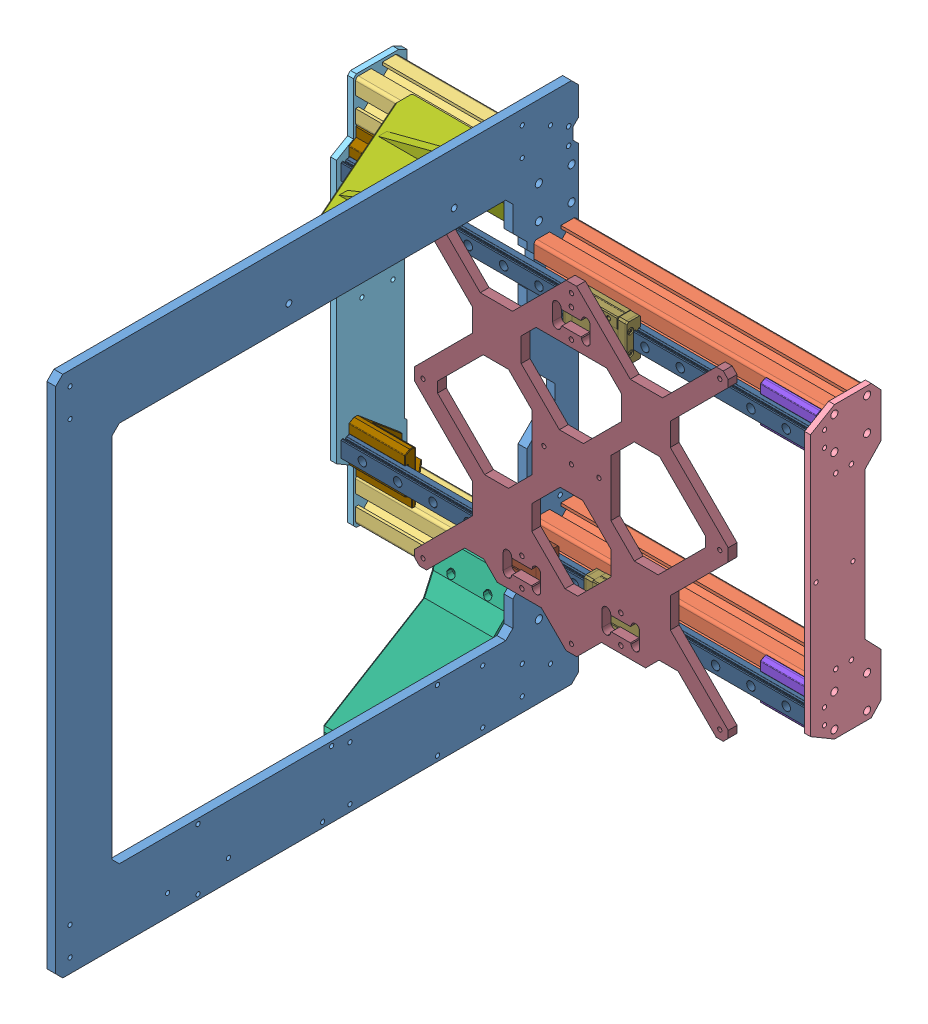
SolidWorks assembly Prusa Frame, configuration Default. Lengths in mm.
Overall size (339.55 370 375).
19 component instances, 13 part files, 54 mates.
Components (placement in the parent):
- Z Frame-2: Z Frame [Default] x (0 1 0) z (1 0 0) size (370 370 6.25)
- 3030 205mm-1: 3030 205mm [Default] at (0 -85 -156.75) x (0 0 -1) z (1 0 0) size (30 30 205)
- 3030 205mm-2: 3030 205mm [Default] at (0 85 -156.75) x (0 0 -1) z (1 0 0) size (30 30 205)
- 3030 120mm-1: 3030 120mm [Default] at (-126.25 -122 -156.75) x (0 1 0) z (1 0 0) size (30 30 120)
- 3030 120mm-2: 3030 120mm [Default] at (-126.25 122 -156.75) x (0 1 0) z (1 0 0) size (30 30 120)
- Front Plate-1: Front Plate [Default] at (0 0 -128.25) x (0 1 0) z (0 0 1) size (205 4.15 50)
- Rear Plate-1: Rear Plate [Default] at (-130.4 0 -175.25) x (0 1 0) z (1 0 0) size (278 50 4.15)
- Einsey Frame Brace-1: Einsey Frame Brace [Default] at (-6.25 -185 -173.25) x (-1 0 0) z (0 0 1) size (56.01 42 143.3)
- PSU Frame Brace-1: PSU Frame Brace [Default] at (-6.25 -185 -173.25) x (-1 0 0) z (0 0 1) size (86.01 54.03 191)
- MGN12 Front-1: MGN12 Front [Default] at (165 -85 -141.75) x (0 -1 0) z (-1 0 0) size (28.98 6 40)
- MGN12 Rear-1: MGN12 Rear [Left] at (-126.25 -107 -141.75) x (0 1 0) z (1 0 0) size (37.75 35 40)
- MGN12 Rear-3: MGN12 Rear [Left] at (-86.25 107 -141.75) x (0 -1 0) z (-1 0 0) size (37.75 35 40)
- MGN12 Front-3: MGN12 Front [Default] at (165 85 -141.75) x (0 -1 0) z (-1 0 0) size (28.98 6 40)
- MGN12 330mm Rail-1: MGN12 330mm Rail [Default] at (-110.5 -85 -138.75) size (330 12 8.07)
- MGN12 330mm Rail-2: MGN12 330mm Rail [Default] at (189.5 85 -138.75) x (-1 0 0) z (0 0 1) size (330 12 8.07)
- MGN12C-1: MGN12C [Default] at (-11.1526 -85 -135.75) size (34.7 27 10)
- MGN12H-1: MGN12H [Default] at (50.9974 -85 -135.75) size (45.4 27 10)
- MGN12H-2: MGN12H [Default] at (35.9974 85 -135.75) size (45.4 27 10)
- Bed Frame-1: Bed Frame [Default] at (48.6974 -1.5 -125.75) x (0 1 0) z (0 0 1) size (227 222 6.25)
Mates (geometry in assembly coordinates):
- Coincident4: coincident: point of Z Frame-2
- Parallel1: parallel aligned: plane of Z Frame-2 through (0 0 0) normal (1 0 0)
- Parallel2: parallel aligned: plane of Z Frame-2 through (0 0 0) normal (0 1 0)
- Coincident6: coincident anti-aligned: plane of Z Frame-2 through (0 0 0) normal (1 0 0); plane of 3030 205mm-1 through (0 -72 -169.75) normal (-1 0 0)
- Concentric4: concentric anti-aligned: cylinder of Z Frame-2 through (-6.25 73.4 -145.15) axis (1 0 0) radius 2.55; cylinder of 3030 205mm-2 through (205 73.4 -145.15) axis (-1 0 0) radius 2.55
- Coincident7: coincident anti-aligned: plane of Z Frame-2 through (0 0 0) normal (1 0 0); plane of 3030 205mm-2 through (0 98 -169.75) normal (-1 0 0)
- Concentric5: concentric anti-aligned: cylinder of Z Frame-2 through (-6.25 96.6 -168.35) axis (1 0 0) radius 2.55; cylinder of 3030 205mm-2 through (205 96.6 -168.35) axis (-1 0 0) radius 2.55
- Concentric6: concentric anti-aligned: cylinder of Z Frame-2 through (-6.25 -96.6 -145.15) axis (1 0 0) radius 2.55; cylinder of 3030 205mm-1 through (205 -96.6 -145.15) axis (-1 0 0) radius 2.55
- Concentric7: concentric anti-aligned: cylinder of Z Frame-2 through (-6.25 -73.4 -168.35) axis (1 0 0) radius 2.55; cylinder of 3030 205mm-1 through (205 -73.4 -168.35) axis (-1 0 0) radius 2.55
- Concentric8: concentric anti-aligned: cylinder of Z Frame-2 through (-6.25 -133.6 -145.15) axis (1 0 0) radius 2.55; cylinder of 3030 120mm-1 through (-6.25 -133.6 -145.15) axis (-1 0 0) radius 2.55
- Coincident8: coincident anti-aligned: plane of Z Frame-2 through (-6.25 0 0) normal (-1 0 0); plane of 3030 120mm-1 through (-6.25 -135 -169.75) normal (1 0 0)
- Concentric9: concentric anti-aligned: cylinder of Z Frame-2 through (-6.25 -110.4 -168.35) axis (1 0 0) radius 2.55; cylinder of 3030 120mm-1 through (-6.25 -110.4 -168.35) axis (-1 0 0) radius 2.55
- Concentric10: concentric anti-aligned: cylinder of Z Frame-2 through (-6.25 133.6 -145.15) axis (1 0 0) radius 2.55; cylinder of 3030 120mm-2 through (-6.25 133.6 -145.15) axis (-1 0 0) radius 2.55
- Concentric11: concentric anti-aligned: cylinder of Z Frame-2 through (-6.25 110.4 -168.35) axis (1 0 0) radius 2.55; cylinder of 3030 120mm-2 through (-6.25 110.4 -168.35) axis (-1 0 0) radius 2.55
- Coincident9: coincident anti-aligned: plane of Z Frame-2 through (-6.25 0 0) normal (-1 0 0); plane of 3030 120mm-2 through (-6.25 109 -169.75) normal (1 0 0)
- Concentric12: concentric aligned: cylinder of 3030 205mm-2 through (205 96.6 -145.15) axis (-1 0 0) radius 2.55; cylinder of Front Plate-1 through (209.15 96.6 -145.15) axis (-1 0 0) radius 2.5
- Coincident10: coincident anti-aligned: plane of 3030 205mm-2 through (205 98 -169.75) normal (1 0 0); plane of Front Plate-1 through (205 0 -128.25) normal (-1 0 0)
- Concentric13: concentric aligned: cylinder of 3030 205mm-1 through (205 -96.6 -168.35) axis (-1 0 0) radius 2.55; cylinder of Front Plate-1 through (209.15 -96.6 -168.35) axis (-1 0 0) radius 2.5
- Concentric14: concentric aligned: cylinder of 3030 120mm-1 through (-6.25 -133.6 -145.15) axis (-1 0 0) radius 2.55; cylinder of Rear Plate-1 through (-126.25 -133.6 -145.15) axis (-1 0 0) radius 2.5
- Coincident11: coincident anti-aligned: plane of 3030 120mm-2 through (-126.25 109 -169.75) normal (-1 0 0); plane of Rear Plate-1 through (-126.25 0 -175.25) normal (1 0 0)
- Concentric15: concentric aligned: cylinder of 3030 120mm-2 through (-6.25 133.6 -168.35) axis (-1 0 0) radius 2.55; cylinder of Rear Plate-1 through (-126.25 133.6 -168.35) axis (-1 0 0) radius 2.5
- Tangent2: tangent anti-aligned: plane of Z Frame-2 through (-6.25 0 0) normal (-1 0 0); face of ?
- Tangent3: tangent anti-aligned: plane of 3030 120mm-1 through (-6.25 -126 -141.75) normal (0 0 1); edge_curve of ?
- Tangent4: tangent anti-aligned: plane of 3030 120mm-1 through (-6.25 -137 -143.75) normal (0 -1 0); edge_curve of ?
- Tangent5: tangent anti-aligned: plane of Z Frame-2 through (-6.25 0 0) normal (-1 0 0); edge_curve of ?
- Tangent6: tangent anti-aligned: plane of 3030 120mm-2 through (-6.25 135 -141.75) normal (0 0 1); edge_curve of ?
- Tangent7: tangent anti-aligned: plane of 3030 120mm-2 through (-6.25 137 -152.75) normal (0 1 0); edge_curve of ?
- Coincident12: coincident anti-aligned: plane of 3030 205mm-1 through (205 -72 -141.75) normal (0 0 1); plane of MGN12 Front-1 through (205 -85 -141.75) normal (0 0 -1)
- Coincident13: coincident anti-aligned: plane of Front Plate-1 through (205 0 -128.25) normal (-1 0 0); plane of MGN12 Front-1 through (205 -72.0113 -140.25) normal (1 0 0)
- Coincident14: coincident anti-aligned: plane of 3030 205mm-1 through (205 -89 -143.75) normal (0 1 0); plane of MGN12 Front-1 through (165 -89 -142.75) normal (0 -1 0)
- Coincident15: coincident anti-aligned: plane of Front Plate-1 through (205 0 -128.25) normal (-1 0 0); plane of MGN12 Front-2 through (205 98.2774 -140.75) normal (1 0 0)
- Coincident16: coincident anti-aligned: plane of 3030 205mm-2 through (205 98 -141.75) normal (0 0 1); plane of MGN12 Front-2 through (205 81 -141.75) normal (0 0 -1)
- Coincident17: coincident anti-aligned: plane of 3030 205mm-2 through (205 89 -141.75) normal (0 -1 0); plane of MGN12 Front-2 through (205 89 -142.75) normal (0 1 0)
- Coincident18: coincident anti-aligned: plane of Rear Plate-1 through (-126.25 0 -175.25) normal (1 0 0); plane of MGN12 Rear-1 through (-126.25 -90.713 -138.4714) normal (-1 0 0)
- Coincident19: coincident anti-aligned: plane of 3030 120mm-1 through (-6.25 -107 -152.75) normal (0 1 0); plane of MGN12 Rear-1 through (-86.25 -107 -141.75) normal (0 -1 0)
- Coincident20: coincident anti-aligned: plane of 3030 120mm-1 through (-6.25 -109 -152.75) normal (0 0 -1); plane of MGN12 Rear-1 through (-126.25 -108 -152.75) normal (0 0 1)
- Distance1: distance = 0.5 mm anti-aligned: plane of MGN12 330mm Rail-1 through (204.5 -85 -138.75) normal (1 0 0); plane of Front Plate-1 through (205 0 -128.25) normal (-1 0 0)
- Coincident23: coincident anti-aligned: plane of MGN12 330mm Rail-1 through (-125.5 -79.5 -130.75) normal (0 0 1); plane of MGN12C-1 through (-4.6526 -90.5 -130.75) normal (0 0 -1)
- Coincident24: coincident anti-aligned: plane of MGN12 330mm Rail-1 through (-125.5 -79.5 -130.75) normal (0 0 1); plane of MGN12H-1 through (57.4974 -90.5 -130.75) normal (0 0 -1)
- Coincident25: coincident anti-aligned: plane of MGN12 330mm Rail-2 through (204.5 79.5 -130.75) normal (0 0 1); plane of MGN12H-2 through (42.4974 79.5 -130.75) normal (0 0 -1)
- Concentric16: concentric aligned: cylinder of MGN12C-1 through (13.6974 -95 -127.5) axis (0 0 -1) radius 1.2295; cylinder of Bed Frame-1 through (13.6974 -95 -119.5) axis (0 0 -1) radius 1.6
- Coincident26: coincident anti-aligned: plane of MGN12C-1 through (-4.6526 -97.9 -125.75) normal (0 0 1); plane of Bed Frame-1 through (48.6974 -1.5 -125.75) normal (0 0 -1)
- Coincident27: coincident anti-aligned: plane of MGN12H-1 through (57.4974 -97.9 -125.75) normal (0 0 1); plane of Bed Frame-1 through (48.6974 -1.5 -125.75) normal (0 0 -1)
- Concentric17: concentric aligned: cylinder of MGN12H-1 through (83.6974 -95 -127.5) axis (0 0 -1) radius 1.2295; cylinder of Bed Frame-1 through (83.6974 -95 -119.5) axis (0 0 -1) radius 1.6
- Coincident28: coincident anti-aligned: plane of MGN12H-2 through (42.4974 91.4 -125.75) normal (0 0 1); plane of Bed Frame-1 through (48.6974 -1.5 -125.75) normal (0 0 -1)
- Concentric18: concentric aligned: cylinder of MGN12H-2 through (48.6974 95 -127.5) axis (0 0 -1) radius 1.2295; cylinder of Bed Frame-1 through (48.6974 95 -119.5) axis (0 0 -1) radius 1.6
- Coincident29: coincident anti-aligned: plane of MGN12 330mm Rail-2 through (204.5 91 -131.25) normal (0 1 0); plane of MGN12H-2 through (42.4974 91 -134.6079) normal (0 -1 0)
- Coincident30: coincident anti-aligned: plane of MGN12 330mm Rail-1 through (-125.5 -91 -131.25) normal (0 -1 0); plane of MGN12H-1 through (57.4974 -91 -138.25) normal (0 1 0)
- Coincident32: coincident anti-aligned: plane of MGN12 330mm Rail-1 through (-125.5 -91 -131.25) normal (0 -1 0); plane of MGN12C-1 through (-4.6526 -91 -138.25) normal (0 1 0)
- LimitDistance3: limit distance = 115.0974 mm anti-aligned: plane of MGN12C-1 through (-11.1526 -85 -131.0047) normal (-1 0 0); plane of Rear Plate-1 through (-126.25 0 -175.25) normal (1 0 0)
- Coincident33: coincident anti-aligned: plane of MGN12 Front-1 through (205 -90.4343 -138.75) normal (0 0 1); plane of MGN12 330mm Rail-1 through (-125.5 -79.5 -138.75) normal (0 0 -1)
- Coincident34: coincident anti-aligned: plane of MGN12 Front-3 through (205 79.5657 -138.75) normal (0 0 1); plane of MGN12 330mm Rail-2 through (204.5 79.5 -138.75) normal (0 0 -1)
- Coincident35: coincident anti-aligned: plane of MGN12 Rear-1 through (-86.25 -90.426 -138.75) normal (0 0 1); plane of MGN12 330mm Rail-1 through (-125.5 -79.5 -138.75) normal (0 0 -1)
- Coincident36: coincident anti-aligned: plane of MGN12 Rear-3 through (-126.25 90.426 -138.75) normal (0 0 1); plane of MGN12 330mm Rail-2 through (204.5 79.5 -138.75) normal (0 0 -1)
